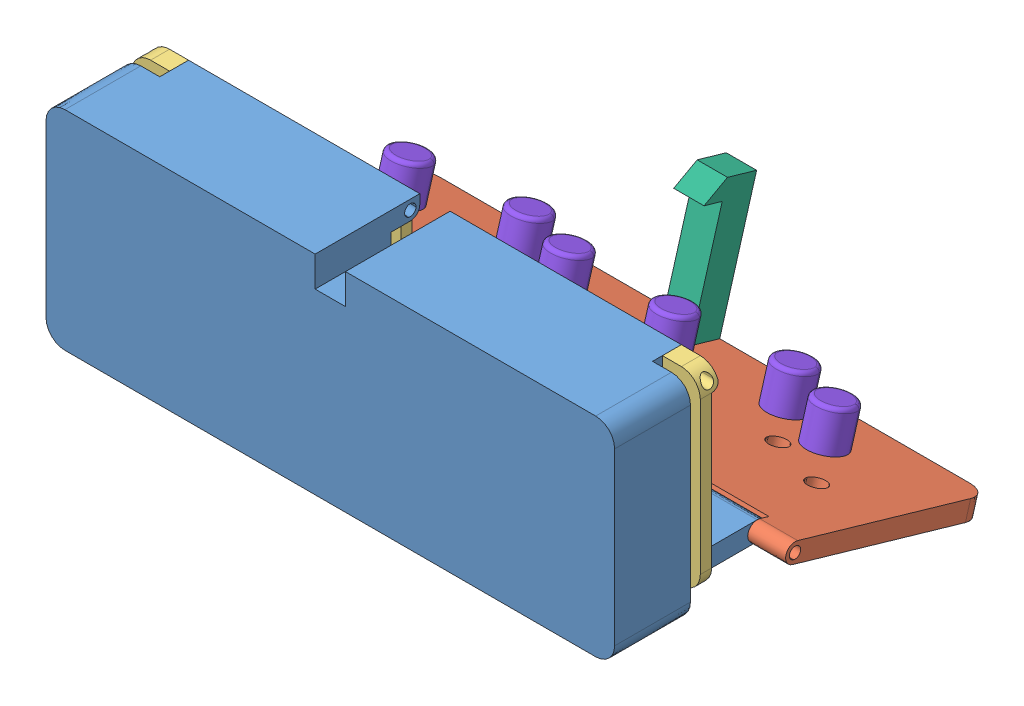
SolidWorks assembly posage insertion p1p2, configuration Default. Lengths in mm.
Overall size (150.01 92.51 112.21).
15 component instances, 8 part files, 0 mates.
Components (placement in the parent):
- posage insertion p1p2.STEP-1: posage insertion p1p2.STEP [Défaut] at origin size (150.01 92.51 112.21)
  - Assem1.STEP.STEP-1: Assem1.STEP.STEP [Défaut] at origin size (150.01 92.51 112.21)
    - Part1_D_faut.STEP.STEP-1: Part1_D_faut.STEP.STEP [Défaut] at (142.2842 -64.1556 130.1877) x (-1 0 0) z (0 0 -1) size (150 55 50.1)
    - Part4_D_faut.STEP.STEP-1: Part4_D_faut.STEP.STEP [Défaut] at (-7.7158 -69.7522 80.8815) x (1 0 0) z (0 0.960561 -0.278069) size (150 55 5)
    - Part2_D_faut.STEP.STEP-1: Part2_D_faut.STEP.STEP [Défaut] at (-7.7158 -64.1556 104.5877) size (150.01 50 5.01)
    - Part3-1_D_faut.STEP.STEP-1: Part3-1_D_faut.STEP.STEP [Défaut] at (62.2842 -57.6556 125.9877) x (-1 0 0) z (0 0 -1) size (60 35.5 23.9)
    - Part3_D_faut.STEP.STEP-1: Part3_D_faut.STEP.STEP [Défaut] at (132.2842 -57.6556 125.9877) x (-1 0 0) z (0 0 -1) size (60 35.5 23.9)
    - Part5_D_faut.STEP.STEP-1: Part5_D_faut.STEP.STEP [Défaut] at (71.2842 -85.2733 41.6502) x (0 0.960561 -0.278069) z (-1 0 0) size (62.82 16.91 8)
    - Part6_D_faut.STEP.STEP-1: Part6_D_faut.STEP.STEP [Défaut] at (76.2842 -98.6958 52.8232) x (-1 0 0) z (0 0.960561 -0.278069) size (18 15 20)
    - Part7_D_faut.STEP.STEP-1: Part7_D_faut.STEP.STEP [Défaut] at (55.1842 -63.1574 57.6307) x (0.923728 -0.106514 -0.367942) z (0 0.960561 -0.278069) size (10 10 10)
    - Part7_D_faut.STEP.STEP-2: Part7_D_faut.STEP.STEP [Défaut] at (83.0842 -63.1574 57.6307) x (0.923728 -0.106514 -0.367942) z (0 0.960561 -0.278069) size (10 10 10)
    - Part7_D_faut.STEP.STEP-3: Part7_D_faut.STEP.STEP [Défaut] at (38.9842 -65.6499 51.8977) x (0.923728 -0.106514 -0.367942) z (0 0.960561 -0.278069) size (10 10 10)
    - Part7_D_faut.STEP.STEP-4: Part7_D_faut.STEP.STEP [Défaut] at (108.9842 -65.6499 51.8977) x (0.923728 -0.106514 -0.367942) z (0 0.960561 -0.278069) size (10 10 10)
    - Part7_D_faut.STEP.STEP-5: Part7_D_faut.STEP.STEP [Défaut] at (125.1842 -63.1574 57.6307) x (0.923728 -0.106514 -0.367942) z (0 0.960561 -0.278069) size (10 10 10)
    - Part7_D_faut.STEP.STEP-6: Part7_D_faut.STEP.STEP [Défaut] at (13.0842 -63.1574 57.6307) x (0.923728 -0.106514 -0.367942) z (0 0.960561 -0.278069) size (10 10 10)
